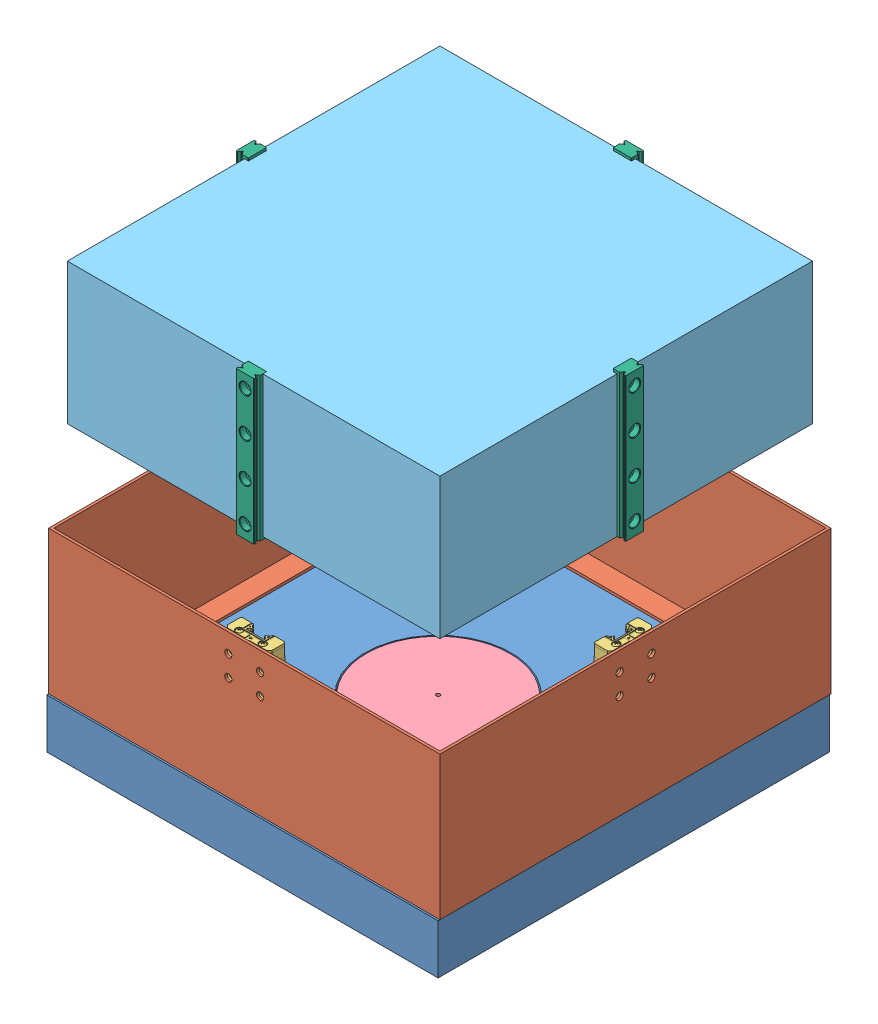
SolidWorks assembly full assem, configuration Default. Lengths in mm.
Overall size (152.16 167.33 150.68).
15 component instances, 7 part files, 11 mates.
Components (placement in the parent):
- base-1: base [Default] at (-146.0607 24.6439 89.3009) size (150 19 150)
- rails boxes-1: rails boxes [Default] at (-93.1569 -15.1404 -115.6602) size (150 60.41 150)
  - rails-1: rails [Default] at (22.0962 113.7843 129.2829) size (150 60 150)
  - MGN7C-1: MGN7C [MGN7C] at (21.9962 102.5343 200.0329) x (-1 0 0) z (0 1 0) size (17 6.5 23.31)
  - MGN7C-2: MGN7C [MGN7C] at (-48.6538 102.5343 129.1829) x (0 0 1) z (0 -1 0) size (17 6.5 23.31)
  - MGN7C-3: MGN7C [MGN7C] at (92.8462 102.5343 129.3829) x (0 0 -1) z (0 -1 0) size (17 6.5 23.31)
  - MGN7C-4: MGN7C [MGN7C] at (22.1962 102.5343 58.5329) x (1 0 0) z (0 1 0) size (17 6.5 23.31)
- flywheel-1: flywheel [Default] at (-71.0607 40.6439 14.3009) x (0.974406 0 0.224797) z (-0.224797 0 0.974406) size (55 3 55)
- top with rails-1: top with rails [Default] at (-176.6707 95.2217 109.8985) x (0.999684 0.025132 0) z (-0.025132 0.999684 0) size (150.74 149.4 58.74)
  - testmotor topmount-1: testmotor topmount [Default] at (36.415 167.772 91.1107) x (0.999684 0 -0.025132) z (0 1 0) size (142.8 54 142.8)
  - MGN7 rail-2: MGN7 rail [150 mm] at (178.7125 96.372 33.5163) x (0 -1 0) z (0.025132 0 0.999684) size (7 4.8 55)
  - MGN7 rail-5: MGN7 rail [150 mm] at (106.4353 168.672 35.3334) x (0.999684 0 -0.025132) z (0.025132 0 0.999684) size (7 4.8 55)
  - MGN7 rail-6: MGN7 rail [150 mm] at (35.5404 96.372 92.133) x (0 -1 0) z (-0.025132 0 -0.999684) size (7 4.8 55)
  - MGN7 rail-7: MGN7 rail [150 mm] at (107.7924 24.072 89.3163) x (0.999684 0 -0.025132) z (-0.025132 0 -0.999684) size (7 4.8 55)
- testmotor with holder-1: testmotor with holder [Default] at (-71.157 145.9188 13.5264) x (1 0 0) z (0 0 -1) size (19.05 20.96 23.81)
Mates (geometry in assembly coordinates):
- Concentric1: concentric anti-aligned: circle of base-1; circle of rails boxes-1/rails-1
- Parallel1: parallel aligned: line of base-1 through (-146.0607 43.6439 89.3009) axis (1 0 0); line of rails boxes-1/rails-1 through (-146.0607 43.6439 88.6227) axis (1 0 0)
- Coincident3: coincident anti-aligned: plane of base-1 through (-146.0607 43.6439 89.3009) normal (0 1 0); plane of rails boxes-1/rails-1 through (-71.0607 43.6439 13.6227) normal (0 -1 0)
- Concentric2: concentric aligned: circle of base-1; circle of flywheel-1
- Coincident6: coincident anti-aligned: plane of base-1 through (-71.0607 40.6439 14.3009) normal (0 1 0); plane of flywheel-1 through (-71.0607 40.6439 14.3009) normal (0 -1 0)
- Coincident9: coincident anti-aligned: plane of rails boxes-1/MGN7C-1 through (-73.497 98.6439 84.3727) normal (1 0 0); plane of top with rails-1/MGN7 rail-7 through (-73.497 132.2188 86.4764) normal (-1 0 0)
- Coincident10: coincident anti-aligned: plane of rails boxes-1/MGN7C-2 through (-141.8107 98.6439 11.1863) normal (0 0 1); plane of top with rails-1/MGN7 rail-6 through (-144.107 133.2188 11.1863) normal (0 0 -1)
- Coincident13: coincident anti-aligned: plane of top with rails-1/testmotor topmount-1 through (-142.557 145.9188 -57.8736) normal (0 -1 0); plane of testmotor with holder-1 through (-71.157 145.9188 13.5264) normal (0 1 0)
- Parallel3: parallel aligned: line of top with rails-1/testmotor topmount-1 through (-61.632 133.2188 29.4014) axis (-1 0 0); line of testmotor with holder-1 through (-61.632 139.5688 29.4014) axis (-1 0 0)
- Coincident16: coincident anti-aligned: plane of top with rails-1/testmotor topmount-1 through (-142.557 145.9188 29.4014) normal (0 0 -1); plane of testmotor with holder-1 through (-71.157 139.5688 29.4014) normal (0 0 1)
- Coincident17: coincident anti-aligned: plane of top with rails-1/testmotor topmount-1 through (-61.632 145.9188 -57.8736) normal (-1 0 0); plane of testmotor with holder-1 through (-61.632 139.5688 13.5264) normal (1 0 0)
